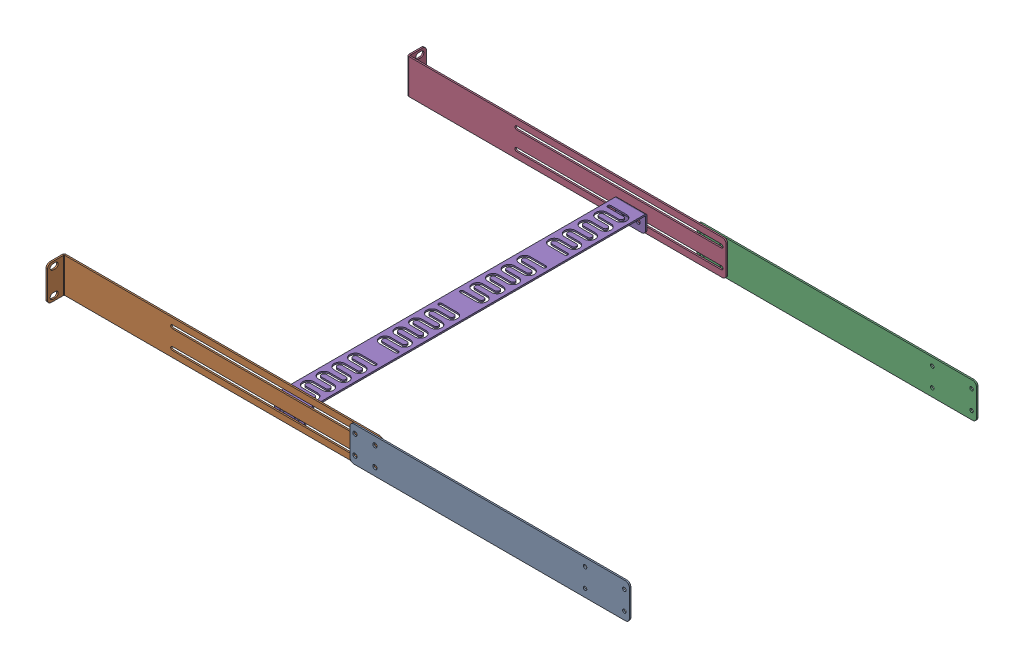
SolidWorks assembly Full rear assembly, configuration Default. Lengths in mm.
Overall size (723.12 44.2 482.47).
7 component instances, 3 part files, 6 mates.
Components (placement in the parent):
- Rear mounting brackets-1: Rear mounting brackets [Default] at (-178.5852 47.8394 61.7356) size (723.12 44.2 23.11)
  - Extension plate-1: Extension plate [Default] at origin size (355.6 44.2 1.88)
  - Rear ears-1: Rear ears [Default] at (-367.5234 0 -1.8796) size (406.4 44.2 23.11)
- Rear mounting brackets-2: Rear mounting brackets [Default] at (-178.5852 92.0354 -382.0236) x (1 0 0) z (0 0 -1) size (723.12 44.2 23.11)
  - Extension plate-1: Extension plate [Default] at origin size (355.6 44.2 1.88)
  - Rear ears-1: Rear ears [Default] at (-367.5234 0 -1.8796) size (406.4 44.2 23.11)
- Optional lacing bar-1: Optional lacing bar [Default] at (-278.5195 68.9974 57.976) x (0 0 -1) z (-1 0 0) size (436.24 23.04 38.1)
Mates (geometry in assembly coordinates):
- Coincident2: coincident aligned: plane of Rear mounting brackets-1/Rear ears-1 through (-546.1087 47.8394 59.856) normal (-1 0 0); plane of Rear mounting brackets-2/Rear ears-1 through (-546.1087 92.0354 -380.144) normal (-1 0 0)
- Coincident3: coincident aligned: plane of Rear mounting brackets-1/Rear ears-1 through (-546.1087 47.8394 81.09) normal (0 -1 0); plane of Rear mounting brackets-2/Rear ears-1 through (-546.1087 47.8394 -380.144) normal (0 -1 0)
- Distance1: distance = 440 mm anti-aligned: plane of Rear mounting brackets-1/Extension plate-1 through (-178.5852 47.8394 59.856) normal (0 0 -1); plane of Rear mounting brackets-2/Extension plate-1 through (-178.5852 92.0354 -380.144) normal (0 0 1)
- Coincident8: coincident anti-aligned: plane of Rear mounting brackets-1/Rear ears-1 through (-546.1087 47.8394 57.976) normal (0 0 -1); plane of Optional lacing bar-1 through (-278.5195 68.9974 57.976) normal (0 0 1)
- Width2: width anti-aligned: plane of Optional lacing bar-1 through (-278.5195 68.9974 57.976) normal (0 -1 0); plane of Optional lacing bar-1 through (-278.5195 70.8774 57.976) normal (0 1 0); plane of Rear mounting brackets-1/Rear ears-1 through (-546.1087 92.0354 57.976) normal (0 1 0); plane of Rear mounting brackets-1/Rear ears-1 through (-546.1087 47.8394 57.976) normal (0 -1 0)
- Slot1: slot aligned: cylinder of Rear mounting brackets-1/Rear ears-1; cylinder of Optional lacing bar-1 through (-249.9445 57.8394 -378.264) axis (0 0 1) radius 2.7051; cylinder of Rear mounting brackets-1/Rear ears-1 through (-406.4087 57.8394 57.976) axis (0 0 1) radius 2.2225
